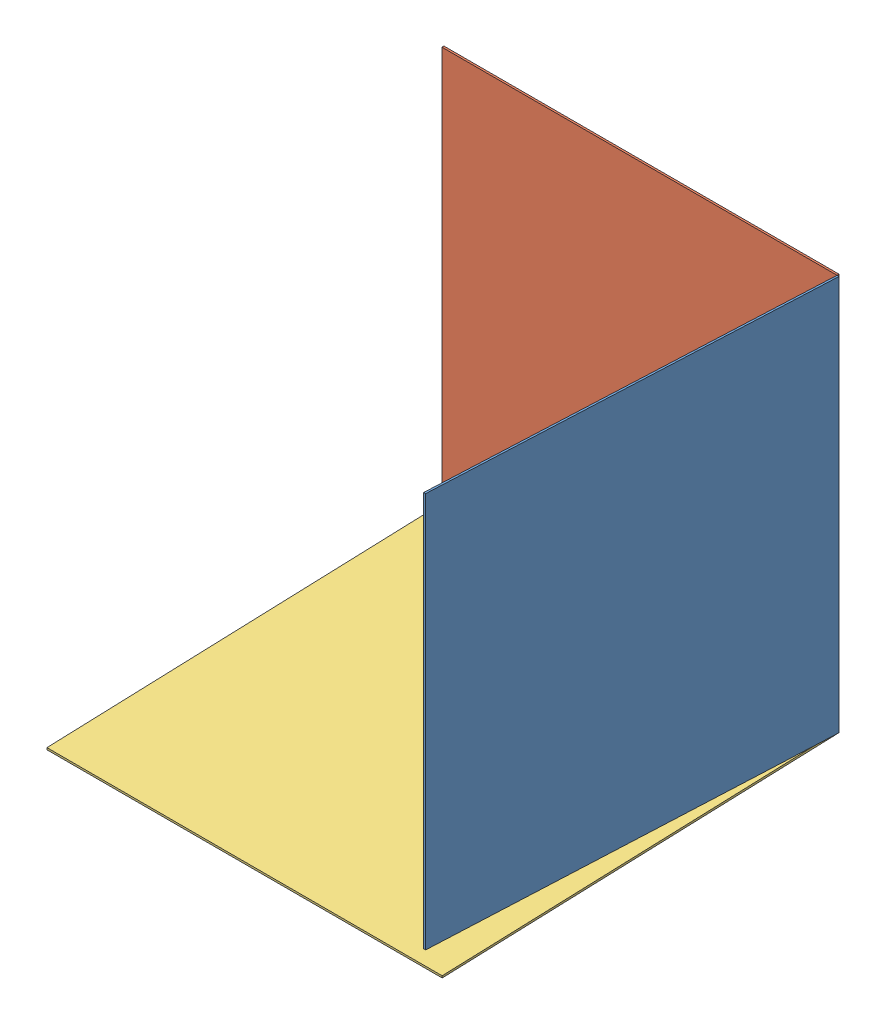
SolidWorks assembly 模型1, configuration 默认. Lengths in mm.
Overall size (201 208.07 200.87).
3 component instances, 3 part files, 6 mates.
Components (placement in the parent):
- 侧视图-1: 侧视图 [默认] at (63.9467 1.1657 400.3891) x (0.998891 0 0.047088) z (-0.047088 0 0.998891) size (1 200 200)
- 正视图-1: 正视图 [默认] at (-31.3445 1.1657 299.5) size (200 200 1)
- 俯视图-1: 俯视图 [默认] at (-31.3445 -103.3696 400.4021) x (1 0 0) z (0 -0.035359 0.999375) size (200 1 200)
Mates (geometry in assembly coordinates):
- 重合1: coincident aligned: line of 侧视图-1 through (68.6555 -98.8343 300.5) axis (0 1 0); line of 正视图-1 through (68.6555 -98.8343 300.5) axis (0 1 0)
- 重合2: coincident: point of 侧视图-1; point of 正视图-1
- 重合3: coincident anti-aligned: line of 正视图-1 through (-131.3445 -98.8343 300.5) axis (1 0 0); line of 俯视图-1 through (68.6555 -98.8343 300.5) axis (-1 0 0)
- 重合4: coincident: point of 侧视图-1; point of 俯视图-1
- 重合5: coincident: plane of 俯视图-1 through (-31.3445 -102.3702 400.4375) normal (0 0.999375 0.035359); point of assembly
- 重合9: coincident: plane of 侧视图-1 through (63.9467 1.1657 400.3891) normal (-0.998891 0 -0.047088); point of assembly
